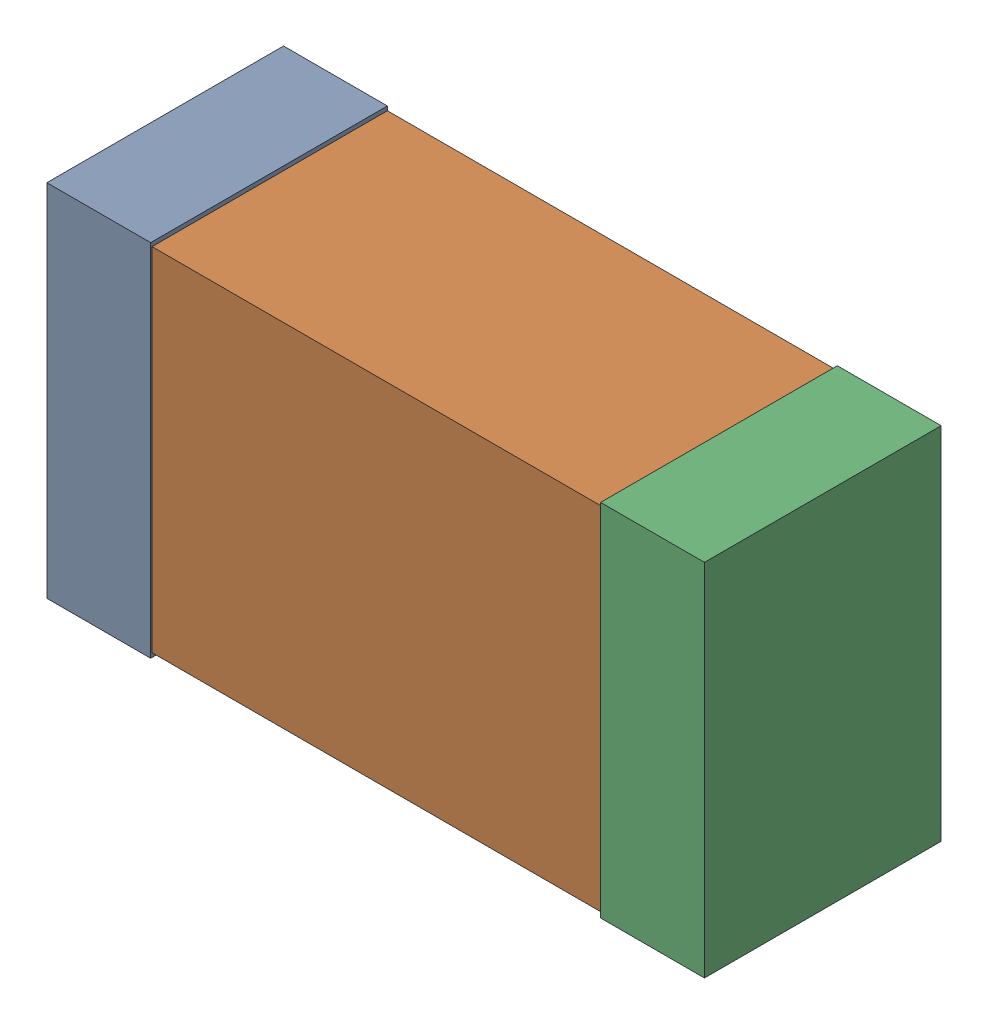
SolidWorks assembly R6Kanaloa_v2.0.0_GPIO_b, configuration Default. Lengths in mm.
Overall size (2.38 1.3 0.85).
6 component instances, 2 part files, 0 mates.
Components (placement in the parent):
- 352877648-1: 352877648 [Default] at (117.618 31.115 0) size (0.38 1.3 0.85)
  - Extruded_14-1: Extruded_14 [Default] at origin size (0.38 1.3 0.85)
- 352877904-1: 352877904 [Default] at (118.618 31.115 0) size (2.2 1.27 0.85)
  - Extruded_18-1: Extruded_18 [Default] at origin size (2.2 1.27 0.85)
- 352877648-2: 352877648 [Default] at (119.618 31.115 0) size (0.38 1.3 0.85)
  - Extruded_14-1: Extruded_14 [Default] at origin size (0.38 1.3 0.85)
